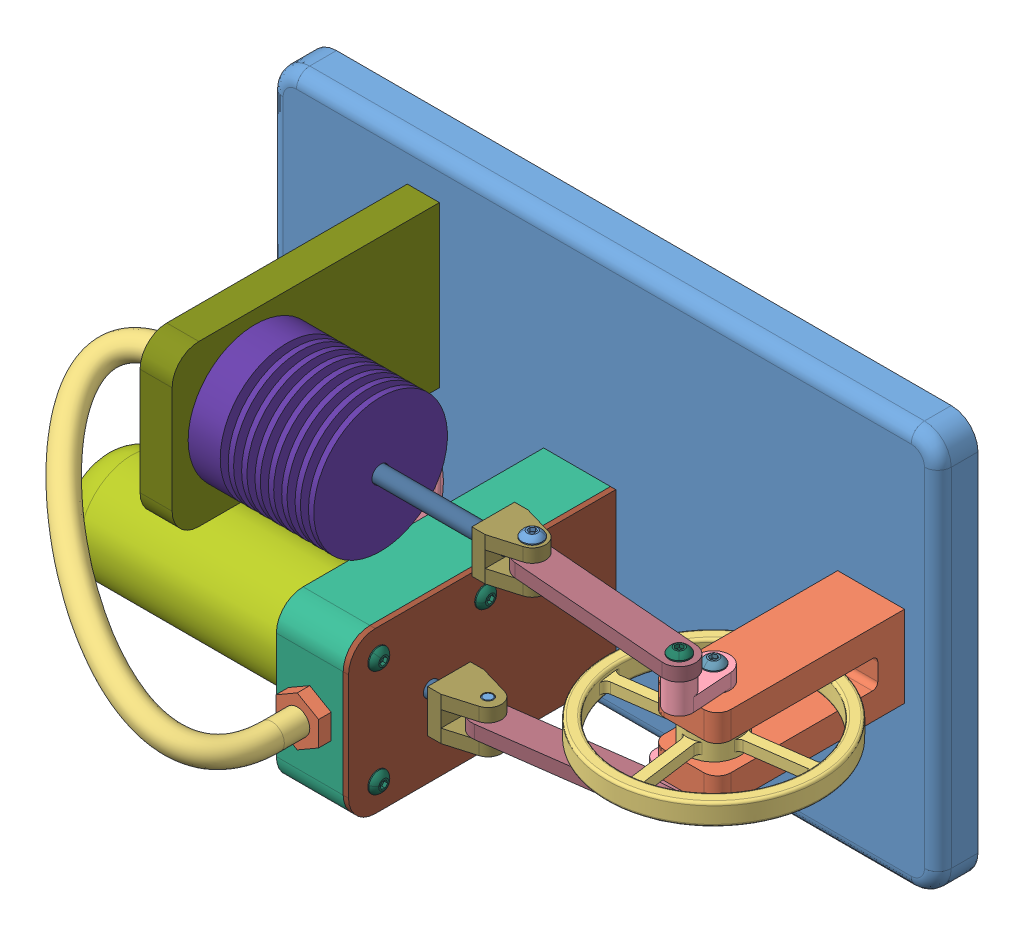
SolidWorks assembly Stirling Engine, configuration Default. Lengths in mm.
Overall size (270.05 150 160.74).
46 component instances, 23 part files, 111 mates.
Components (placement in the parent):
- P4 Base-1: P4 Base [Default] at origin size (250 150 15)
- P2 Flywheel bracket-1: P2 Flywheel bracket [Default] at (100 0 15) x (0 -1 0) z (-1 0 0) size (30.5 70 25)
- P1 Flywheel-1: P1 Flywheel [Default] at (100 0 73.9) x (0 1 0) z (0.135406 0 0.99079) size (8 80 80)
- P3 Crank-1: P3 Crank [Default] at (100 18.25 73.9) x (0.99079 0 -0.135406) z (0 -1 0) size (12 26 23.5)
- P3 Crank-2: P3 Crank [Default] at (100 -18.25 73.9) x (-0.135406 0 -0.99079) z (0 1 0) size (12 26 23.5)
- P6 M4x25_4_8h-1: P6 M4x25_4_8h [Default] at (100 10.25 0) size (8.4 8.4 25)
- P6 M4x25_4_8h-2: P6 M4x25_4_8h [Default] at (100 -10.25 0) x (0.987351 0.158553 0) z (0 0 1) size (8.4 8.4 25)
- P7 Heater Bracket-1: P7 Heater Bracket [Default] at (-10 -30 65) x (0 1 0) z (0 0 -1) size (60 25 100)
- P9 Heater Cylinder-1: P9 Heater Cylinder [Default] at (2.5 -30 84) x (1 0 0) z (0 1 0) size (122 41.5 41.5)
- P10 Heater Pistaon-1: P10 Heater Pistaon [Default] at (-101.9168 -30 84) x (-1 0 0) z (0 -0.366595 0.930381) size (50 34.5 34.5)
- P11 Pistom Cap-1: P11 Pistom Cap [Default] at (-106.9168 -30 84) x (1 0 0) z (0 -0.036913 0.999318) size (15 34.5 34.5)
- P12 Piston Rod-1: P12 Piston Rod [Default] at (-18.9168 -30 84) x (0 0.508036 0.861336) z (-1 0 0) size (6.32 6 70.74)
- P8 Heater Bracket Cover-2: P8 Heater Bracket Cover [Default] at (3.5 -30 65) x (0 -1 0) z (-1 0 0) size (60 100 2)
- P13 Rod Connector-1: P13 Rod Connector [Default] at (13.5832 -30 84) x (0 -1 0) z (0 0 1) size (16 19.6 16)
- P14 Linkage-1: P14 Linkage [Default] at (55.4107 -30 79.9655) x (0.990916 0 -0.134482) z (0 1 0) size (72 12 5)
- P6 M4x25_4_8h-3: P6 M4x25_4_8h [Default] at (-10 -10 0) x (0.970788 -0.239939 0) z (0 0 1) size (8.4 8.4 25)
- P6 M4x25_4_8h-8: P6 M4x25_4_8h [Default] at (-10 -50 0) x (0.987351 0.158553 0) z (0 0 1) size (8.4 8.4 25)
- P15 m4x20socketbuttonhead-1: P15 m4x20socketbuttonhead [Default] at (100 -22.95 73.9) x (0 1 0) z (-0.955476 0 -0.295069) size (22.2 7.6 7.6)
- P15 m4x20socketbuttonhead-2: P15 m4x20socketbuttonhead [Default] at (100 22.95 73.9) x (0 -1 0) z (-0.999994 0 0.003507) size (22.2 7.6 7.6)
- P16 m4x10socketbuttonhead-1: P16 m4x10socketbuttonhead [Default] at (6.7 -10 104) x (-1 0 0) z (0 -0.607975 0.793956) size (12.2 7.6 7.6)
- P16 m4x10socketbuttonhead-2: P16 m4x10socketbuttonhead [Default] at (6.7 -50 104) x (-1 0 0) z (0 0.985432 -0.17007) size (12.2 7.6 7.6)
- P16 m4x10socketbuttonhead-4: P16 m4x10socketbuttonhead [Default] at (6.7 -50 64) x (-1 0 0) z (0 -0.984477 0.175513) size (12.2 7.6 7.6)
- P16 m4x10socketbuttonhead-6: P16 m4x10socketbuttonhead [Default] at (6.7 -10 64) x (-1 0 0) z (0 -0.999998 0.001894) size (12.2 7.6 7.6)
- P17 Cooler Braket-1: P17 Cooler Braket [Default] at (-67.5 30 65) x (0 -1 0) z (-1 0 0) size (60 100 12)
- P18 Cooler Cylinder-1: P18 Cooler Cylinder [Default] at (-14.5 30 84) size (47 50 50)
- P19 Cooler Cylinder-1: P19 Cooler Cylinder [Default] at (-32.3797 30 84) x (0 0.300247 0.953862) z (-1 0 0) size (36 36 5)
- P12 Piston Rod-2: P12 Piston Rod [Default] at (-2.3797 30 84) x (0 -0.329439 -0.944177) z (-1 0 0) size (6.32 6 70.74)
- P13 Rod Connector-2: P13 Rod Connector [Default] at (30.1203 30 84) x (0 -1 0) z (0 0 1) size (16 19.6 16)
- P14 Linkage-2: P14 Linkage [Default] at (72.1257 30 86.3809) x (-0.996846 0 -0.079364) z (0 1 0) size (72 12 5)
- P6 M4x25_4_8h-9: P6 M4x25_4_8h [Default] at (-67.5 50 0) x (0.970788 -0.239939 0) z (0 0 1) size (8.4 8.4 25)
- P6 M4x25_4_8h-10: P6 M4x25_4_8h [Default] at (-67.5 10 0) x (0.996551 -0.082983 0) z (0 0 1) size (8.4 8.4 25)
- P15 m4x20socketbuttonhead-3: P15 m4x20socketbuttonhead [Default] at (-75.7 51.5 84) x (1 0 0) z (0 -0.010031 -0.99995) size (22.2 7.6 7.6)
- P15 m4x20socketbuttonhead-4: P15 m4x20socketbuttonhead [Default] at (-75.7 30 105.5) x (1 0 0) z (0 0.148641 -0.988891) size (22.2 7.6 7.6)
- P15 m4x20socketbuttonhead-6: P15 m4x20socketbuttonhead [Default] at (-75.7 8.5 84) x (1 0 0) z (0 0.273349 -0.961915) size (22.2 7.6 7.6)
- P15 m4x20socketbuttonhead-8: P15 m4x20socketbuttonhead [Default] at (-75.7 30 62.5) x (1 0 0) z (0 0.361821 -0.932248) size (22.2 7.6 7.6)
- P16 m4x10socketbuttonhead-8: P16 m4x10socketbuttonhead [Default] at (85.1381 -34.7 75.9311) x (0 1 0) z (0.319956 0 -0.947433) size (12.2 7.6 7.6)
- P16 m4x10socketbuttonhead-9: P16 m4x10socketbuttonhead [Default] at (102.0311 34.7 88.7619) x (0 -1 0) z (-0.719835 0 0.694145) size (12.2 7.6 7.6)
- P20 m4x16socketbuttonhead-1: P20 m4x16socketbuttonhead [Default] at (25.6832 -40.2 84) x (0 1 0) z (0.800005 0 0.599993) size (18.2 7.6 7.6)
- P20 m4x16socketbuttonhead-2: P20 m4x16socketbuttonhead [Default] at (42.2203 40.2 84) x (0 -1 0) z (0.599993 0 0.800005) size (18.2 7.6 7.6)
- P21 Air Volve-1: P21 Air Volve [Default] at (-64 30 84) x (0 0.866025 -0.5) z (-1 0 0) size (16 18.48 23.7)
- P21 Air Volve-2: P21 Air Volve [Default] at (-10 -30 105.5) x (-0.5 0.866025 0) z (0 0 1) size (16 18.48 23.7)
- P22 Connecting Tube^Stirling Engine-1: P22 Connecting Tube^Stirling Engine [Default] at (0 0 119.7) size (109.96 70.23 82.3) (virtual)
- P22 BurnerPlate-1: P22 BurnerPlate [Default] at (-90 -30 15) x (0 -1 0) z (0 0 1) size (60 60 2)
- P23 m4x10-1: P23 m4x10 [Default] at (-101 -10.9474 17) x (0.382682 0.92388 0) z (0 0 -1) size (8.4 8.4 10)
- P23 m4x10-2: P23 m4x10 [Default] at (-101 -49.0526 17) x (0.231358 0.972869 0) z (0 0 -1) size (8.4 8.4 10)
- P23 m4x10-4: P23 m4x10 [Default] at (-68 -30 17) x (0.105597 0.994409 0) z (0 0 -1) size (8.4 8.4 10)
Mates (geometry in assembly coordinates):
- Coincident1: coincident anti-aligned: plane of P4 Base-1 through (0 0 15) normal (0 0 1); plane of P2 Flywheel bracket-1 through (87.5 0 15) normal (0 0 -1)
- Coincident3: coincident anti-aligned: plane of P4 Base-1 through (0 0 0) normal (0 1 0); plane of P2 Flywheel bracket-1 through (100 0 15) normal (0 -1 0)
- Distance1: distance = 100 mm anti-aligned: plane of P4 Base-1 through (0 0 0) normal (1 0 0); plane of P2 Flywheel bracket-1 through (100 0 15) normal (-1 0 0)
- Coincident7: coincident anti-aligned: plane of P2 Flywheel bracket-1 through (100 0 15) normal (0 -1 0); plane of P1 Flywheel-1 through (100 0 73.9) normal (0 1 0)
- Concentric3: concentric anti-aligned: cylinder of P2 Flywheel bracket-1 through (100 15.25 73.9) axis (0 -1 0) radius 6.1; cylinder of P1 Flywheel-1 through (100 0 73.9) axis (0 1 0) radius 2.75
- Concentric4: concentric anti-aligned: cylinder of P2 Flywheel bracket-1 through (100 15.25 73.9) axis (0 -1 0) radius 6.1; cylinder of P3 Crank-1 through (100 15.75 73.9) axis (0 1 0) radius 6
- Coincident8: coincident anti-aligned: plane of P1 Flywheel-1 through (97.2753 4 74.2724) normal (0 1 0); plane of P3 Crank-1 through (100 4 73.9) normal (0 -1 0)
- Parallel4: parallel anti-aligned: plane of P1 Flywheel-1 through (100 0 73.9) normal (-0.99079 0 0.135406); plane of P3 Crank-1 through (100 18.25 73.9) normal (0.99079 0 -0.135406)
- Concentric5: concentric aligned: cylinder of P2 Flywheel bracket-1 through (100 15.25 73.9) axis (0 -1 0) radius 6.1; cylinder of P3 Crank-2 through (100 -15.75 73.9) axis (0 -1 0) radius 6
- Coincident11: coincident anti-aligned: plane of P1 Flywheel-1 through (97.2753 -4 74.2724) normal (0 -1 0); plane of P3 Crank-2 through (100 -4 73.9) normal (0 1 0)
- Parallel5: parallel anti-aligned: plane of P1 Flywheel-1 through (100 0 73.9) normal (0.135406 0 0.99079); plane of P3 Crank-2 through (100 -18.25 73.9) normal (-0.135406 0 -0.99079)
- Concentric6: concentric anti-aligned: cylinder of P3 Crank-1 through (100 4 73.9) axis (0 -1 0) radius 1.65; cylinder of dineniso7046-2m3x208_8h2-1 through (100 11.0806 73.9) axis (0 1 0) radius 1.5
- Coincident14: coincident aligned: circle of P3 Crank-1; cone of dineniso7046-2m3x208_8h2-1 through (100 21.286 73.9) axis (0 -1 0)
- Concentric8: concentric anti-aligned: cylinder of P3 Crank-2 through (100 -4 73.9) axis (0 1 0) radius 1.65; cylinder of dineniso7046-2m3x208_8h2-2 through (100 -11.0806 73.9) axis (0 -1 0) radius 1.5
- Coincident15: coincident aligned: circle of P3 Crank-2; cone of dineniso7046-2m3x208_8h2-2 through (100 -21.286 73.9) axis (0 1 0)
- Concentric9: concentric aligned: cylinder of P4 Base-1 through (100 10.25 0) axis (0 0 -1) radius 2.25; cylinder of P6 M4x25_4_8h-1 through (100 10.25 13.855) axis (0 0 -1) radius 2
- Coincident16: coincident aligned: plane of P4 Base-1 through (0 0 0) normal (0 0 -1); plane of P6 M4x25_4_8h-1 through (100 12.35 0) normal (0 0 -1)
- Concentric10: concentric aligned: cylinder of P4 Base-1 through (100 -10.25 0) axis (0 0 -1) radius 2.25; cylinder of P6 M4x25_4_8h-2 through (100 -10.25 13.855) axis (0 0 -1) radius 2
- Coincident17: coincident aligned: plane of P4 Base-1 through (0 0 0) normal (0 0 -1); plane of P6 M4x25_4_8h-2 through (99.667 -8.1766 0) normal (0 0 -1)
- Coincident18: coincident anti-aligned: plane of P4 Base-1 through (0 0 15) normal (0 0 1); plane of P7 Heater Bracket-1 through (-10 -30 15) normal (0 0 -1)
- Coincident20: coincident aligned: plane of P4 Base-1 through (0 0 0) normal (0 0 1)
- Coincident21: coincident aligned: plane of P4 Base-1 through (0 0 0) normal (0 1 0)
- Coincident22: coincident aligned: plane of P4 Base-1 through (0 0 0) normal (1 0 0)
- Distance6: distance = 10 mm aligned: plane of P7 Heater Bracket-1 through (-10 -30 65) normal (1 0 0)
- Distance7: distance = 30 mm: plane of assembly through (0 0 0) normal (0 1 0); plane of assembly; plane of P7 Heater Bracket-1 through (-10 -30 65) normal (0 1 0)
- Concentric11: concentric aligned: cylinder of P7 Heater Bracket-1 through (-22.5 -30 84) axis (1 0 0) radius 20; cylinder of P9 Heater Cylinder-1 through (2.5 -30 84) axis (1 0 0) radius 19.75
- Concentric12: concentric aligned: cone of P7 Heater Bracket-1 through (-10 -30 115) axis (0 0 -1); cylinder of P9 Heater Cylinder-1 through (-10 -30 104.751) axis (0 0 -1) radius 5
- Concentric13: concentric aligned: cylinder of P10 Heater Pistaon-1 through (-101.9168 -30 84) axis (-1 0 0) radius 15.25; cylinder of P11 Pistom Cap-1 through (-106.9168 -30 84) axis (-1 0 0) radius 15.25
- Coincident28: coincident anti-aligned: plane of P10 Heater Pistaon-1 through (-101.9168 -44.1883 78.4094) normal (-1 0 0); plane of P11 Pistom Cap-1 through (-101.9168 -12.7618 84.6368) normal (1 0 0)
- Concentric14: concentric aligned: cylinder of P10 Heater Pistaon-1 through (-51.9168 -30 84) axis (1 0 0) radius 2.5; cylinder of P12 Piston Rod-1 through (-53.9168 -30 84) axis (1 0 0) radius 3
- Coincident29: coincident aligned: circle of P10 Heater Pistaon-1; plane of P12 Piston Rod-1 through (-53.9168 -30 84) normal (-1 0 0)
- Concentric15: concentric anti-aligned: cylinder of P9 Heater Cylinder-1 through (2.5 -30 84) axis (1 0 0) radius 17.75; cylinder of P10 Heater Pistaon-1 through (-101.9168 -30 84) axis (-1 0 0) radius 17.25
- Concentric16: concentric anti-aligned: cylinder of P12 Piston Rod-1 through (-53.9168 -30 84) axis (1 0 0) radius 3; cylinder of P8 Heater Bracket Cover-2 through (4.5 -30 84) axis (-1 0 0) radius 3
- Parallel7: parallel anti-aligned: line of P7 Heater Bracket-1 through (-22.5 0 15) axis (0 0 1); line of P8 Heater Bracket Cover-2 through (4.5 0 105) axis (0 0 -1)
- Coincident31: coincident anti-aligned: plane of P7 Heater Bracket-1 through (2.5 -60 15) normal (1 0 0); plane of P8 Heater Bracket Cover-2 through (2.5 -30 65) normal (-1 0 0)
- Concentric17: concentric anti-aligned: cylinder of P12 Piston Rod-1 through (-53.9168 -30 84) axis (1 0 0) radius 3; cylinder of P13 Rod Connector-1 through (11.0832 -30 84) axis (-1 0 0) radius 2.5
- Coincident32: coincident aligned: plane of P12 Piston Rod-1 through (16.0832 -30 84) normal (1 0 0); plane of P13 Rod Connector-1 through (16.0832 -38 84) normal (1 0 0)
- Parallel8: parallel aligned: plane of P7 Heater Bracket-1 through (-22.5 0 15) normal (0 1 0); plane of P13 Rod Connector-1 through (13.5832 -22 84) normal (0 1 0)
- Concentric18: concentric anti-aligned: cylinder of P13 Rod Connector-1 through (25.6832 -38 84) axis (0 1 0) radius 2; cylinder of P14 Linkage-1 through (25.6832 -27.5 84) axis (0 -1 0) radius 2.25
- Concentric19: concentric anti-aligned: cylinder of P3 Crank-2 through (85.1381 -4 75.9311) axis (0 1 0) radius 1.65; cylinder of P14 Linkage-1 through (85.1381 -27.5 75.9311) axis (0 -1 0) radius 2.25
- Coincident34: coincident anti-aligned: plane of P3 Crank-2 through (85.1381 -27.5 75.9311) normal (0 -1 0); plane of P14 Linkage-1 through (85.1381 -27.5 75.9311) normal (0 1 0)
- Concentric21: concentric aligned: cylinder of P4 Base-1 through (-10 -50 0) axis (0 0 -1) radius 2.25; cylinder of P6 M4x25_4_8h-8 through (-10 -50 13.855) axis (0 0 -1) radius 2
- Coincident36: coincident aligned: plane of P4 Base-1 through (0 0 0) normal (0 0 -1); plane of P6 M4x25_4_8h-8 through (-10.333 -47.9266 0) normal (0 0 -1)
- Concentric22: concentric aligned: circle of P4 Base-1; cylinder of P6 M4x25_4_8h-3 through (-10 -10 13.855) axis (0 0 -1) radius 2
- Coincident37: coincident aligned: plane of P4 Base-1 through (0 0 0) normal (0 0 -1); plane of P6 M4x25_4_8h-3 through (-9.4961 -7.9613 0) normal (0 0 -1)
- Concentric23: concentric aligned: cylinder of P8 Heater Bracket Cover-2 through (2.5 -10 104) axis (-1 0 0) radius 2.25; cylinder of P15 243004x10-2 through (5.1636 -10 104) axis (-1 0 0) radius 2
- Concentric24: concentric anti-aligned: cylinder of P3 Crank-1 through (100 4 73.9) axis (0 -1 0) radius 1.65; cylinder of m4x20socketbuttonhead.step-2 through (100 22.95 73.9) axis (0 1 0) radius 2
- Coincident38: coincident anti-aligned: plane of P3 Crank-1 through (100 20.75 73.9) normal (0 1 0); plane of m4x20socketbuttonhead.step-2 through (100.007 20.75 75.9) normal (0 -1 0)
- Concentric25: concentric anti-aligned: cylinder of P3 Crank-2 through (100 -4 73.9) axis (0 1 0) radius 1.65; cylinder of m4x20socketbuttonhead.step-1 through (100 -22.95 73.9) axis (0 -1 0) radius 2
- Coincident39: coincident anti-aligned: plane of P3 Crank-2 through (100 -20.75 73.9) normal (0 -1 0); plane of m4x20socketbuttonhead.step-1 through (100.5901 -20.75 71.989) normal (0 1 0)
- Concentric26: concentric aligned: cylinder of P7 Heater Bracket-1 through (2.5 -10 104) axis (1 0 0) radius 1.65; cylinder of m4x10socketbuttonhead.step-1 through (6.7 -10 104) axis (1 0 0) radius 2
- Coincident40: coincident anti-aligned: plane of P8 Heater Bracket Cover-2 through (4.5 -30 65) normal (1 0 0); plane of m4x10socketbuttonhead.step-1 through (4.5 -11.5879 102.7841) normal (-1 0 0)
- Concentric27: concentric anti-aligned: cylinder of P8 Heater Bracket Cover-2 through (2.5 -50 104) axis (-1 0 0) radius 2.25; cylinder of m4x10socketbuttonhead.step-2 through (6.7 -50 104) axis (1 0 0) radius 2
- Coincident41: coincident anti-aligned: plane of P8 Heater Bracket Cover-2 through (4.5 -30 65) normal (1 0 0); plane of m4x10socketbuttonhead.step-2 through (4.5 -49.6599 105.9709) normal (-1 0 0)
- Concentric28: concentric anti-aligned: cylinder of P8 Heater Bracket Cover-2 through (2.5 -50 64) axis (-1 0 0) radius 2.25; cylinder of m4x10socketbuttonhead.step-4 through (6.7 -50 64) axis (1 0 0) radius 2
- Coincident42: coincident anti-aligned: plane of P8 Heater Bracket Cover-2 through (4.5 -30 65) normal (1 0 0); plane of m4x10socketbuttonhead.step-4 through (4.5 -50.351 62.031) normal (-1 0 0)
- Concentric29: concentric anti-aligned: cylinder of P8 Heater Bracket Cover-2 through (2.5 -10 64) axis (-1 0 0) radius 2.25; cylinder of m4x10socketbuttonhead.step-6 through (6.7 -10 64) axis (1 0 0) radius 2
- Coincident43: coincident anti-aligned: plane of P8 Heater Bracket Cover-2 through (4.5 -30 65) normal (1 0 0); plane of m4x10socketbuttonhead.step-6 through (4.5 -10.0038 62) normal (-1 0 0)
- Coincident44: coincident anti-aligned: plane of P4 Base-1 through (0 0 15) normal (0 0 1); plane of P17 Cooler Braket-1 through (-73.5 0 15) normal (0 0 -1)
- Distance8: distance = 30 mm anti-aligned: plane of P17 Cooler Braket-1 through (-67.5 30 65) normal (0 -1 0)
- Distance9: distance = 67.5 mm: plane of assembly through (0 0 0) normal (1 0 0); plane of assembly; plane of P17 Cooler Braket-1 through (-67.5 30 65) normal (-1 0 0)
- Concentric30: concentric anti-aligned: cylinder of P17 Cooler Braket-1 through (-61.5 30 105.5) axis (1 0 0) radius 2.25; cylinder of P18 Cooler Cylinder-1 through (-61.5 30 105.5) axis (-1 0 0) radius 1.65
- Concentric31: concentric aligned: cylinder of P17 Cooler Braket-1 through (-61.5 30 84) axis (1 0 0) radius 5.5626; cylinder of P18 Cooler Cylinder-1 through (-14.5 30 84) axis (1 0 0) radius 18
- Coincident45: coincident anti-aligned: plane of P17 Cooler Braket-1 through (-61.5 30 65) normal (1 0 0); plane of P18 Cooler Cylinder-1 through (-61.5 50 84) normal (-1 0 0)
- Concentric32: concentric anti-aligned: cylinder of P18 Cooler Cylinder-1 through (-59.5 30 84) axis (-1 0 0) radius 25; cylinder of P19 Cooler Cylinder-1 through (-37.3797 30 84) axis (1 0 0) radius 18
- Concentric33: concentric anti-aligned: cylinder of P19 Cooler Cylinder-1 through (-37.3797 30 84) axis (-1 0 0) radius 2.5; cylinder of P12 Piston Rod-2 through (-37.3797 30 84) axis (1 0 0) radius 3
- Coincident46: coincident aligned: circle of P19 Cooler Cylinder-1; plane of P12 Piston Rod-2 through (-37.3797 30 84) normal (-1 0 0)
- Concentric34: concentric anti-aligned: cylinder of P12 Piston Rod-2 through (-37.3797 30 84) axis (1 0 0) radius 3; cylinder of P13 Rod Connector-2 through (27.6203 30 84) axis (-1 0 0) radius 2.5
- Coincident47: coincident aligned: plane of P12 Piston Rod-2 through (32.6203 30 84) normal (1 0 0); circle of P13 Rod Connector-2
- Parallel9: parallel aligned: plane of P7 Heater Bracket-1 through (-22.5 0 15) normal (0 1 0); plane of P13 Rod Connector-2 through (30.1203 38 84) normal (0 1 0)
- Concentric35: concentric anti-aligned: cylinder of P13 Rod Connector-2 through (42.2203 22 84) axis (0 1 0) radius 2; cylinder of P14 Linkage-2 through (42.2203 32.5 84) axis (0 -1 0) radius 2.25
- Concentric36: concentric aligned: cylinder of P3 Crank-1 through (102.0311 4 88.7619) axis (0 -1 0) radius 1.65; cylinder of P14 Linkage-2 through (102.0311 32.5 88.7619) axis (0 -1 0) radius 2.25
- Coincident50: coincident anti-aligned: plane of P3 Crank-1 through (102.0311 27.5 88.7619) normal (0 1 0); plane of P14 Linkage-2 through (42.2203 27.5 84) normal (0 -1 0)
- Concentric37: concentric aligned: cylinder of P4 Base-1 through (-67.5 50 0) axis (0 0 -1) radius 2.25; cylinder of P6 M4x25_4_8h-9 through (-67.5 50 13.855) axis (0 0 -1) radius 2
- Coincident51: coincident aligned: plane of P4 Base-1 through (0 0 0) normal (0 0 -1); plane of P6 M4x25_4_8h-9 through (-66.9961 52.0387 0) normal (0 0 -1)
- Concentric38: concentric aligned: cylinder of P4 Base-1 through (-67.5 10 0) axis (0 0 -1) radius 2.25; cylinder of P6 M4x25_4_8h-10 through (-67.5 10 13.855) axis (0 0 -1) radius 2
- Coincident52: coincident aligned: plane of P4 Base-1 through (0 0 0) normal (0 0 -1); plane of P6 M4x25_4_8h-10 through (-67.3257 12.0928 0) normal (0 0 -1)
- Concentric39: concentric anti-aligned: cylinder of P17 Cooler Braket-1 through (-61.5 51.5 84) axis (1 0 0) radius 2.25; cylinder of P15 m4x20socketbuttonhead-3 through (-75.7 51.5 84) axis (-1 0 0) radius 2
- Coincident53: coincident anti-aligned: plane of P17 Cooler Braket-1 through (-73.5 30 65) normal (-1 0 0); plane of P15 m4x20socketbuttonhead-3 through (-73.5 49.5001 84.0201) normal (1 0 0)
- Concentric40: concentric anti-aligned: cylinder of P17 Cooler Braket-1 through (-61.5 30 105.5) axis (1 0 0) radius 2.25; cylinder of P15 m4x20socketbuttonhead-4 through (-75.7 30 105.5) axis (-1 0 0) radius 2
- Coincident54: coincident anti-aligned: plane of P17 Cooler Braket-1 through (-73.5 30 65) normal (-1 0 0); plane of P15 m4x20socketbuttonhead-4 through (-73.5 28.0222 105.2027) normal (1 0 0)
- Concentric41: concentric anti-aligned: cylinder of P17 Cooler Braket-1 through (-61.5 8.5 84) axis (1 0 0) radius 2.25; cylinder of P15 m4x20socketbuttonhead-6 through (-75.7 8.5 84) axis (-1 0 0) radius 2
- Coincident55: coincident anti-aligned: plane of P17 Cooler Braket-1 through (-73.5 30 65) normal (-1 0 0); plane of P15 m4x20socketbuttonhead-6 through (-73.5 6.5762 83.4533) normal (1 0 0)
- Concentric42: concentric anti-aligned: cylinder of P17 Cooler Braket-1 through (-61.5 30 62.5) axis (1 0 0) radius 2.25; cylinder of P15 m4x20socketbuttonhead-8 through (-75.7 30 62.5) axis (-1 0 0) radius 2
- Coincident56: coincident anti-aligned: plane of P17 Cooler Braket-1 through (-73.5 30 65) normal (-1 0 0); plane of P15 m4x20socketbuttonhead-8 through (-73.5 28.1355 61.7764) normal (1 0 0)
- Concentric43: concentric anti-aligned: cylinder of P13 Rod Connector-1 through (25.6832 -38 84) axis (0 1 0) radius 2; cylinder of P16 m4x10socketbuttonhead-7 through (56.1008 -39.7117 84) axis (0 -1 0) radius 2
- Concentric44: concentric aligned: cylinder of P14 Linkage-1 through (85.1381 -27.5 75.9311) axis (0 -1 0) radius 2.25; cylinder of P16 m4x10socketbuttonhead-8 through (85.1381 -34.7 75.9311) axis (0 -1 0) radius 2
- Coincident57: coincident anti-aligned: plane of P14 Linkage-1 through (85.1381 -32.5 75.9311) normal (0 -1 0); plane of P16 m4x10socketbuttonhead-8 through (87.033 -32.5 76.571) normal (0 1 0)
- Concentric45: concentric anti-aligned: cylinder of P14 Linkage-2 through (102.0311 32.5 88.7619) axis (0 -1 0) radius 2.25; cylinder of P16 m4x10socketbuttonhead-9 through (102.0311 34.7 88.7619) axis (0 1 0) radius 2
- Coincident58: coincident anti-aligned: plane of P14 Linkage-2 through (42.2203 32.5 84) normal (0 1 0); plane of P16 m4x10socketbuttonhead-9 through (103.4194 32.5 90.2015) normal (0 -1 0)
- Concentric46: concentric anti-aligned: cylinder of P13 Rod Connector-1 through (25.6832 -38 84) axis (0 1 0) radius 2; cylinder of P16 m4x10socketbuttonhead-11 through (55.8257 -40.2 84) axis (0 -1 0) radius 2
- Coincident59: coincident anti-aligned: plane of P13 Rod Connector-1 through (13.5832 -38 84) normal (0 -1 0); plane of P16 m4x10socketbuttonhead-11 through (57.3978 -38 82.7637) normal (0 1 0)
- Concentric47: concentric anti-aligned: cylinder of P13 Rod Connector-1 through (25.6832 -38 84) axis (0 1 0) radius 2; cylinder of P20 m4x16socketbuttonhead-1 through (25.6832 -40.2 84) axis (0 -1 0) radius 2
- Coincident60: coincident anti-aligned: plane of P13 Rod Connector-1 through (13.5832 -38 84) normal (0 -1 0); plane of P20 m4x16socketbuttonhead-1 through (24.4832 -38 85.6) normal (0 1 0)
- Concentric48: concentric anti-aligned: cylinder of P13 Rod Connector-2 through (42.2203 38 84) axis (0 -1 0) radius 2; cylinder of P20 m4x16socketbuttonhead-2 through (42.2203 40.2 84) axis (0 1 0) radius 2
- Coincident61: coincident anti-aligned: plane of P13 Rod Connector-2 through (30.1203 38 84) normal (0 1 0); plane of P20 m4x16socketbuttonhead-2 through (43.8204 38 82.8) normal (0 -1 0)
- Concentric49: concentric aligned: cylinder of P17 Cooler Braket-1 through (-61.5 30 84) axis (1 0 0) radius 5.5626; cylinder of P21 Air Volve-1 through (-73.5 30 84) axis (1 0 0) radius 5.1
- Coincident62: coincident anti-aligned: plane of P17 Cooler Braket-1 through (-73.5 30 65) normal (-1 0 0); plane of P21 Air Volve-1 through (-73.5 30 84) normal (1 0 0)
- Parallel10: parallel aligned: plane of P17 Cooler Braket-1 through (-73.5 0 115) normal (0 0 1); plane of P21 Air Volve-1 through (-78.2 25.3812 92) normal (0 0 1)
- Concentric50: concentric aligned: cone of P7 Heater Bracket-1 through (-10 -30 115) axis (0 0 -1); cylinder of P21 Air Volve-2 through (-10 -30 115) axis (0 0 -1) radius 5.1
- Coincident64: coincident anti-aligned: plane of P7 Heater Bracket-1 through (-10 -30 115) normal (0 0 1); plane of P21 Air Volve-2 through (-10 -30 115) normal (0 0 -1)
- Parallel11: parallel aligned: plane of P8 Heater Bracket Cover-2 through (4.5 -30 65) normal (1 0 0); plane of P21 Air Volve-2 through (-2 -34.6188 119.7) normal (1 0 0)
- Coincident65: coincident anti-aligned: plane of P4 Base-1 through (0 0 15) normal (0 0 1); plane of P22 BurnerPlate-1 through (-90 -30 15) normal (0 0 -1)
- Coincident66: coincident anti-aligned: plane of P7 Heater Bracket-1 through (-10 -30 65) normal (0 1 0); plane of P22 BurnerPlate-1 through (-90 -30 15) normal (0 -1 0)
- Distance10: distance = 35 mm anti-aligned: plane of P22 BurnerPlate-1 through (-90 -30 15) normal (1 0 0); plane of P4 Base-1 through (-125 -75 15) normal (-1 0 0)
- Concentric51: concentric aligned: cylinder of P4 Base-1 through (-101 -10.9474 15) axis (0 0 1) radius 1.65; cylinder of P23 m4x10-1 through (-101 -10.9474 10.295) axis (0 0 1) radius 2
- Coincident68: coincident aligned: plane of P22 BurnerPlate-1 through (-90 -30 17) normal (0 0 1); plane of P23 m4x10-1 through (-99.0599 -11.7511 17) normal (0 0 1)
- Coincident70: coincident aligned: plane of P22 BurnerPlate-1 through (-90 -30 17) normal (0 0 1); plane of P23 m4x10-2 through (-98.957 -49.5384 17) normal (0 0 1)
- Concentric53: concentric aligned: cylinder of P4 Base-1 through (-101 -49.0526 15) axis (0 0 1) radius 1.65; cylinder of P23 m4x10-2 through (-101 -49.0526 10.295) axis (0 0 1) radius 2
- Concentric54: concentric aligned: cylinder of P4 Base-1 through (-68 -30 15) axis (0 0 1) radius 1.65; cylinder of P23 m4x10-4 through (-68 -30 10.295) axis (0 0 1) radius 2
- Coincident71: coincident aligned: plane of P22 BurnerPlate-1 through (-90 -30 17) normal (0 0 1); plane of P23 m4x10-4 through (-65.9117 -30.2218 17) normal (0 0 1)
